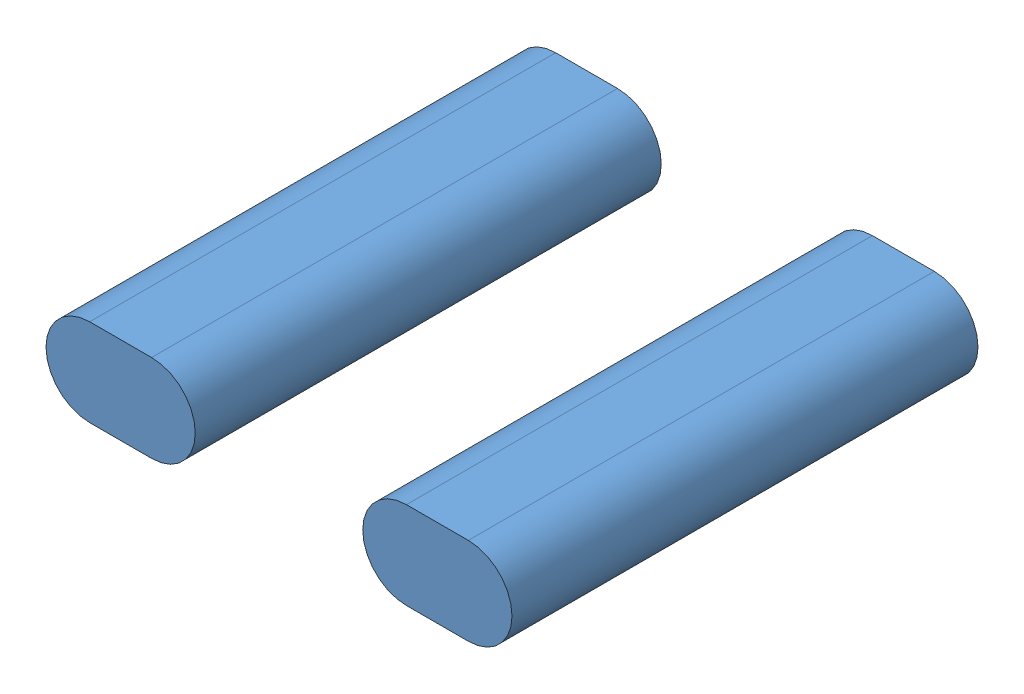
SolidWorks assembly Baugruppe2, configuration Standard. Lengths in mm.
Overall size (128 24 128).
2 component instances, 1 part files, 3 mates.
Components (placement in the parent):
- Batterypack-2: Batterypack [Standard] at origin size (41 24 128)
- Batterypack-3: Batterypack [Standard] at (87 0 0) size (41 24 128)
Mates (geometry in assembly coordinates):
- Deckungsgleich1: coincident: plane of Batterypack-2 through (-8.5 0 128) normal (0 0 1); plane of Batterypack-3 through (180.6389 0 128) normal (0 0 1)
- Deckungsgleich2: coincident: plane of Batterypack-2 through (-8.5 12 128) normal (0 1 0); plane of Batterypack-3 through (180.6389 12 128) normal (0 1 0)
- Abstand2: distance = 128 mm: moEndPointRef_w of Batterypack-2; moEndPointRef_w of Batterypack-3
